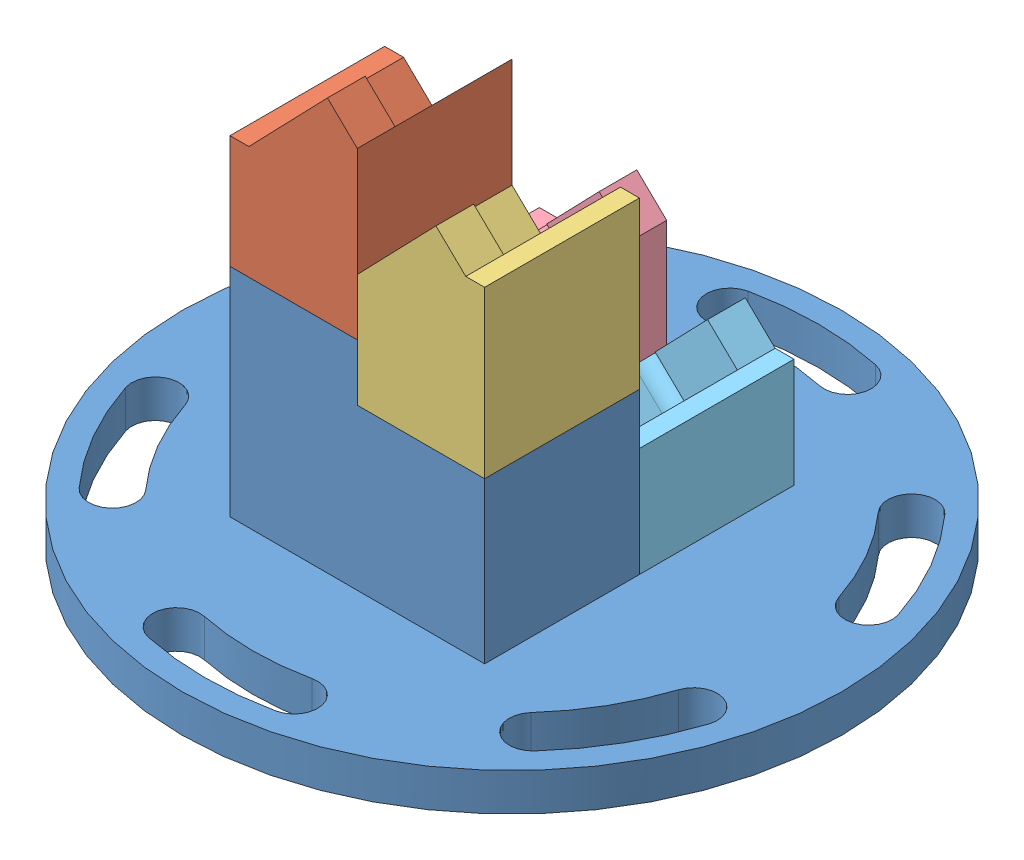
SolidWorks assembly SWD1C9.tmp, configuration Default. Lengths in mm.
Overall size (35 23.82 35).
5 component instances, 6 part files, 13 mates.
Components (placement in the parent):
- Grating Device V3 MPFI-1: Grating Device V3 MPFI [Default] at (-70.471 9.2701 24.3367) size (35 13.5 35)
- Grating Devise V3 Insert 1 MPFI-1: Grating Devise V3 Insert 1 MPFI [Default] at (-70.471 26.7701 32.5367) x (-1 0 0) z (0 0 -1) size (6.75 10.32 8.2)
- Grating Devise V3 Insert 2 MPFI-1: Grating Devise V3 Insert 2 MPFI [Default] at (-70.471 23.7701 24.3367) size (6.75 10.32 8.2)
- Grating Devise V3 Insert 3 MPFI-1: Grating Devise V3 Insert 3 MPFI [Default] at (-70.471 15.2701 24.3367) x (-1 0 0) z (0 0 -1) size (6.75 8.32 8.2)
- Grating Devise V3 Insert 4 MPFI-1: Grating Devise V3 Insert 4 MPFI [Default] at (-63.721 12.2701 24.3367) x (-1 0 0) z (0 0 -1) size (6.75 7.32 8.2)
Mates (geometry in assembly coordinates):
- Lock1: lock: unknown of Grating Device V3 MPFI-1
- Concentric1: concentric anti-aligned: cylinder of Grating Device V3 MPFI-1 through (-72.471 22.7701 25.4367) axis (0 1 0) radius 0.75; cylinder of Grating Devise V3 Insert 1 MPFI-1 through (-72.471 22.7701 25.4367) axis (0 -1 0) radius 0.75
- Concentric2: concentric anti-aligned: cylinder of Grating Device V3 MPFI-1 through (-72.471 22.7701 31.4367) axis (0 1 0) radius 0.75; cylinder of Grating Devise V3 Insert 1 MPFI-1 through (-72.471 22.7701 31.4367) axis (0 -1 0) radius 0.75
- Coincident1: coincident anti-aligned: plane of Grating Device V3 MPFI-1 through (-77.221 22.7701 6.8367) normal (0 1 0); plane of Grating Devise V3 Insert 1 MPFI-1 through (-70.471 22.7701 32.5367) normal (0 -1 0)
- Concentric3: concentric anti-aligned: cylinder of Grating Device V3 MPFI-1 through (-66.721 19.7701 25.4367) axis (0 1 0) radius 0.75; cylinder of Grating Devise V3 Insert 2 MPFI-1 through (-66.721 19.7701 25.4367) axis (0 -1 0) radius 0.75
- Concentric4: concentric anti-aligned: cylinder of Grating Device V3 MPFI-1 through (-66.721 19.7701 31.4367) axis (0 1 0) radius 0.75; cylinder of Grating Devise V3 Insert 2 MPFI-1 through (-66.721 19.7701 31.4367) axis (0 -1 0) radius 0.75
- Coincident2: coincident anti-aligned: plane of Grating Device V3 MPFI-1 through (-70.471 19.7701 6.8367) normal (0 1 0); plane of Grating Devise V3 Insert 2 MPFI-1 through (-70.471 19.7701 24.3367) normal (0 -1 0)
- Concentric5: concentric anti-aligned: cylinder of Grating Device V3 MPFI-1 through (-72.471 13.2701 23.2367) axis (0 1 0) radius 0.75; cylinder of Grating Devise V3 Insert 3 MPFI-1 through (-72.471 13.2701 23.2367) axis (0 -1 0) radius 0.75
- Concentric6: concentric anti-aligned: cylinder of Grating Device V3 MPFI-1 through (-72.471 13.2701 17.2367) axis (0 1 0) radius 0.75; cylinder of Grating Devise V3 Insert 3 MPFI-1 through (-72.471 13.2701 17.2367) axis (0 -1 0) radius 0.75
- Coincident3: coincident anti-aligned: plane of Grating Device V3 MPFI-1 through (-77.221 13.2701 39.11) normal (0 1 0); plane of Grating Devise V3 Insert 3 MPFI-1 through (-70.471 13.2701 24.3367) normal (0 -1 0)
- Concentric7: concentric: cylinder of Grating Device V3 MPFI-1 through (-66.721 11.2701 23.2367) axis (0 1 0) radius 0.75; cylinder of Grating Devise V3 Insert 4 MPFI-1 through (-66.721 13.8952 23.2367) axis (0 -1 0) radius 0.75
- Concentric8: concentric: cylinder of Grating Device V3 MPFI-1 through (-66.721 11.2701 17.2367) axis (0 1 0) radius 0.75; cylinder of Grating Devise V3 Insert 4 MPFI-1 through (-66.721 13.8952 17.2367) axis (0 -1 0) radius 0.75
- Coincident5: coincident anti-aligned: plane of Grating Device V3 MPFI-1 through (-70.471 11.2701 24.3367) normal (0 1 0); plane of Grating Devise V3 Insert 4 MPFI-1 through (-63.721 11.2701 24.3367) normal (0 -1 0)
